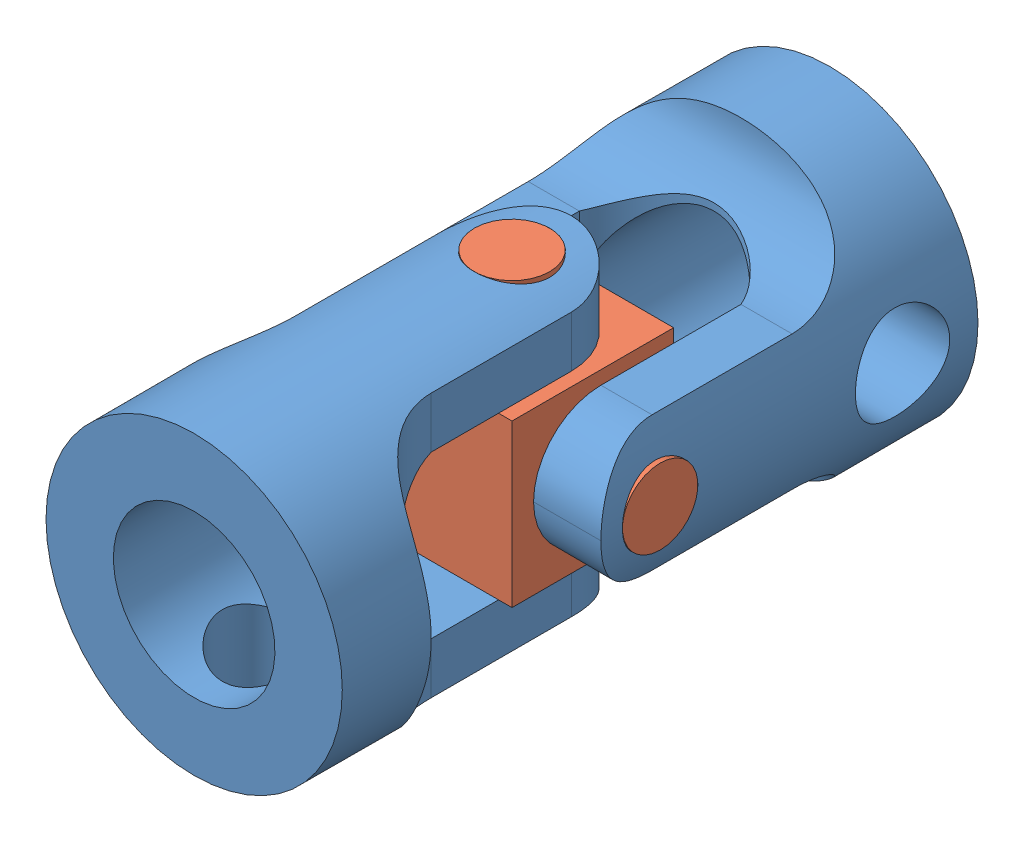
SolidWorks assembly 万向节6x6装配体, configuration 默认. Lengths in mm.
Overall size (11 11 23.6).
3 component instances, 2 part files, 5 mates.
Components (placement in the parent):
- 万向节6x6连接件-1: 万向节6x6连接件 [默认] at origin size (11 11 14)
- 万向节6x6连接件-2: 万向节6x6连接件 [默认] at (0 0 23.6) x (0 -1 0) z (0 0 -1) size (11 11 14)
- 万向节6x6中间件-1: 万向节6x6中间件 [默认] at (0 0 8.8) x (1 0 0) z (0 -1 0) size (11 6 11)
Mates (geometry in assembly coordinates):
- 宽度1: width anti-aligned: plane of 万向节6x6连接件-1 through (-3 -5.5 14) normal (1 0 0); plane of 万向节6x6中间件-1 through (3 -5.5 14) normal (-1 0 0); plane of 万向节6x6连接件-1 through (-3 3 14.8) normal (-1 0 0); plane of 万向节6x6中间件-1 through (3 3 14.8) normal (1 0 0)
- 同心1: concentric anti-aligned: cylinder of 万向节6x6连接件-1 through (-5.5 0 11.8) axis (1 0 0) radius 1.4; cylinder of 万向节6x6中间件-1 through (5.5 0 11.8) axis (-1 0 0) radius 1.4
- 宽度2: width aligned: plane of 万向节6x6连接件-2 through (5.5 3 9.6) normal (0 -1 0); plane of 万向节6x6中间件-1 through (5.5 -3 9.6) normal (0 1 0); plane of 万向节6x6连接件-2 through (-3 -3 14.8) normal (0 -1 0); plane of 万向节6x6中间件-1 through (-3 3 14.8) normal (0 1 0)
- 同心2: concentric anti-aligned: cylinder of 万向节6x6连接件-2 through (0 5.5 11.8) axis (0 -1 0) radius 1.4; cylinder of 万向节6x6中间件-1 through (0 -5.5 11.8) axis (0 1 0) radius 1.4
- 平行1: parallel anti-aligned: plane of 万向节6x6连接件-1 through (0 0 0) normal (0 0 -1); plane of 万向节6x6连接件-2
